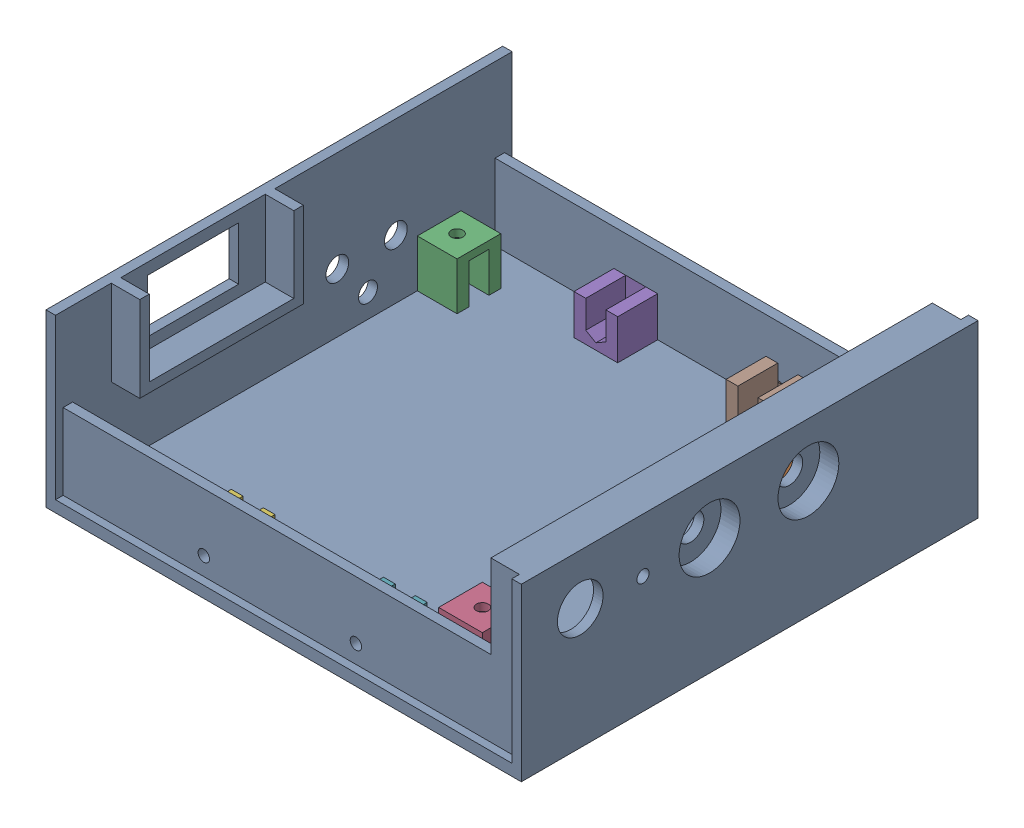
SolidWorks assembly final2, configuration Default. Lengths in mm.
Overall size (125 45 120.1).
8 component instances, 2 part files, 19 mates.
Components (placement in the parent):
- part2-1: part2 [Default] at (-20.267 -12.2865 19.0419) size (125 45 120.1)
- nuthole-1: nuthole [Default] at (15.633 -9.2865 -22.5781) size (11.5 12.5 11.5)
- nuthole-2: nuthole [Default] at (-75.567 -9.2865 -21.8081) x (-1 0 0) z (0 0 -1) size (11.5 12.5 11.5)
- nuthole-4: nuthole [Default] at (12.883 -9.2865 59.9919) size (11.5 12.5 11.5)
- nuthole-6: nuthole [Default] at (-43.267 -4.5365 -26.0081) x (0 -1 0) z (1 0 0) size (11.5 12.5 11.5)
- nuthole-7: nuthole [Default] at (-43.267 -4.5365 64.0919) x (0 -1 0) z (-1 0 0) size (11.5 12.5 11.5)
- nuthole-8: nuthole [Default] at (-3.267 -4.5365 64.0919) x (0 -1 0) z (-1 0 0) size (11.5 12.5 11.5)
- nuthole-9: nuthole [Default] at (-3.267 -4.5365 -26.0081) x (0 -1 0) z (1 0 0) size (11.5 12.5 11.5)
Mates (geometry in assembly coordinates):
- Coincident5: coincident: plane of part2-1 through (-20.267 -9.2865 19.0419) normal (0 1 0); plane of nuthole-1 through (15.633 -9.2865 -22.5781) normal (0 -1 0)
- Coincident6: coincident: plane of part2-1 through (-20.267 -9.2865 19.0419) normal (0 1 0); plane of nuthole-1 through (15.633 -9.2865 -22.5781) normal (0 -1 0)
- Coincident7: coincident: plane of part2-1 through (-20.267 -9.2865 19.0419) normal (0 1 0); plane of nuthole-2 through (-75.567 -9.2865 -21.8081) normal (0 -1 0)
- Coincident8: coincident: plane of part2-1 through (-20.267 -9.2865 19.0419) normal (0 1 0); plane of nuthole-4 through (12.883 -9.2865 59.9919) normal (0 -1 0)
- Distance7: distance = 8.85 mm: plane of nuthole-4 through (7.133 3.2135 65.7419) normal (0 0 1); plane of part2-1 through (-80.267 29.7135 74.5919) normal (0 0 -1)
- Distance9: distance = 71.07 mm: plane of nuthole-4 through (7.133 3.2135 54.2419) normal (0 0 -1); plane of nuthole-1 through (9.883 3.2135 -16.8281) normal (0 0 1)
- Distance15: distance = 79.7 mm: plane of nuthole-1 through (9.883 3.2135 -16.8281) normal (-1 0 0); plane of nuthole-2 through (-69.817 3.2135 -27.5581) normal (1 0 0)
- Distance22: distance = 10.45 mm: plane of part2-1 through (-80.267 29.7135 -36.5081) normal (1 0 0); plane of nuthole-2 through (-69.817 3.2135 -27.5581) normal (1 0 0)
- Concentric2: concentric: cylinder of part2-1 through (-43.267 -4.5365 -41.0081) axis (0 0 1) radius 1.5; cylinder of nuthole-6 through (-43.267 -4.5365 -38.5081) axis (0 0 1) radius 1.55
- Parallel10: parallel: plane of nuthole-2 through (-69.817 3.2135 -27.5581) normal (1 0 0); plane of nuthole-6 through (-49.017 1.2135 -38.5081) normal (-1 0 0)
- Concentric4: concentric: circle of part2-1; cylinder of nuthole-9 through (-3.267 -4.5365 -36.5081) axis (0 0 1) radius 1.55
- Concentric7: concentric: circle of part2-1; cylinder of nuthole-8 through (-3.267 -4.5365 76.5919) axis (0 0 -1) radius 1.55
- Parallel12: parallel: plane of part2-1 through (39.733 29.7135 -36.5081) normal (-1 0 0); plane of nuthole-8 through (2.483 1.2135 76.5919) normal (1 0 0)
- Concentric8: concentric: cylinder of part2-1 through (-43.267 -4.5365 -41.0081) axis (0 0 1) radius 1.5; cylinder of nuthole-7 through (-43.267 -4.5365 76.5919) axis (0 0 -1) radius 1.55
- Parallel13: parallel: plane of part2-1 through (-80.267 29.7135 -36.5081) normal (1 0 0); plane of nuthole-7 through (-49.017 1.2135 76.5919) normal (-1 0 0)
- Coincident31: coincident: plane of part2-1 through (-80.267 29.7135 74.5919) normal (0 0 -1); plane of nuthole-8 through (-3.267 -4.5365 74.5919) normal (0 0 -1)
- Coincident32: coincident: plane of part2-1 through (-80.267 29.7135 74.5919) normal (0 0 -1); plane of nuthole-7 through (-43.267 -4.5365 74.5919) normal (0 0 -1)
- Coincident33: coincident: plane of part2-1 through (-80.267 29.7135 -36.5081) normal (0 0 1); plane of nuthole-6 through (-43.267 -4.5365 -36.5081) normal (0 0 1)
- Coincident34: coincident: plane of part2-1 through (-80.267 29.7135 -36.5081) normal (0 0 1); plane of nuthole-9 through (-3.267 -4.5365 -36.5081) normal (0 0 1)
